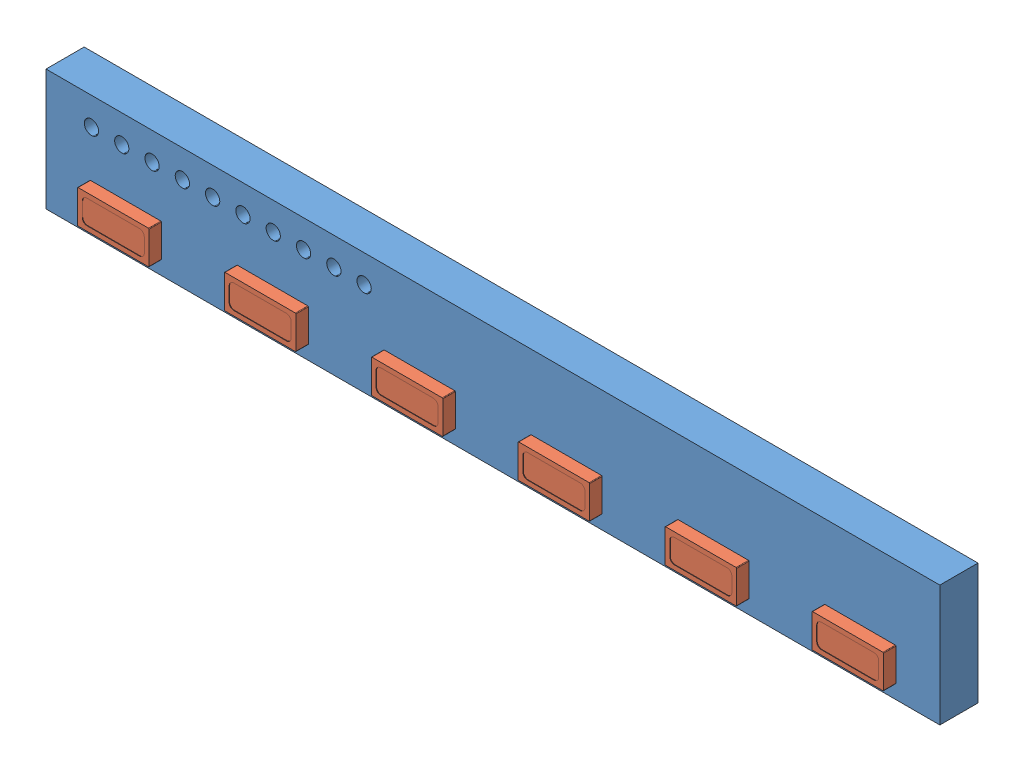
SolidWorks assembly PCB_SIDE_LED_R, configuration Default. Lengths in mm.
Overall size (37.46 5.08 2.12).
7 component instances, 2 part files, 3 mates.
Components (placement in the parent):
- LEDPanel2R-1: LEDPanel2R [Default] at (-12.1342 0.9368 4.9666) size (37.46 5.08 1.6)
- 1206_5000k_LUMINUS_MP3014_1100-1: 1206_5000k_LUMINUS_MP3014_1100 [Default] at (-27.5267 -0.3332 6.5666) x (0 1 0) z (1 0 0) size (1.4 0.52 3)
- 1206_5000k_LUMINUS_MP3014_1100-2: 1206_5000k_LUMINUS_MP3014_1100 [Default] at (-21.3698 -0.3332 6.5666) x (0 1 0) z (1 0 0) size (1.4 0.52 3)
- 1206_5000k_LUMINUS_MP3014_1100-3: 1206_5000k_LUMINUS_MP3014_1100 [Default] at (-15.2128 -0.3332 6.5666) x (0 1 0) z (1 0 0) size (1.4 0.52 3)
- 1206_5000k_LUMINUS_MP3014_1100-4: 1206_5000k_LUMINUS_MP3014_1100 [Default] at (-9.0558 -0.3332 6.5666) x (0 1 0) z (1 0 0) size (1.4 0.52 3)
- 1206_5000k_LUMINUS_MP3014_1100-5: 1206_5000k_LUMINUS_MP3014_1100 [Default] at (-2.8989 -0.3332 6.5666) x (0 1 0) z (1 0 0) size (1.4 0.52 3)
- 1206_5000k_LUMINUS_MP3014_1100-9: 1206_5000k_LUMINUS_MP3014_1100 [Default] at (3.2581 -0.3332 6.5666) x (0 1 0) z (1 0 0) size (1.4 0.52 3)
Mates (geometry in assembly coordinates):
- Coincident1: coincident: plane of LEDPanel2R-1 through (-12.1342 0.9368 6.5666) normal (0 0 1); plane of 1206_5000k_LUMINUS_MP3014_1100-1 through (-29.0017 -0.3732 6.5666) normal (0 0 -1)
- Parallel1: parallel: plane of LEDPanel2R-1 through (-30.8667 -1.6032 6.5666) normal (0 -1 0); plane of 1206_5000k_LUMINUS_MP3014_1100-1 through (-26.0517 1.0018 7.0866) normal (0 1 0)
- Distance1: distance = 1.27 mm: plane of 1206_5000k_LUMINUS_MP3014_1100-1 through (-27.5267 -0.3332 6.5666) normal (0 1 0); plane of LEDPanel2R-1 through (-30.8667 -1.6032 6.5666) normal (0 -1 0)
